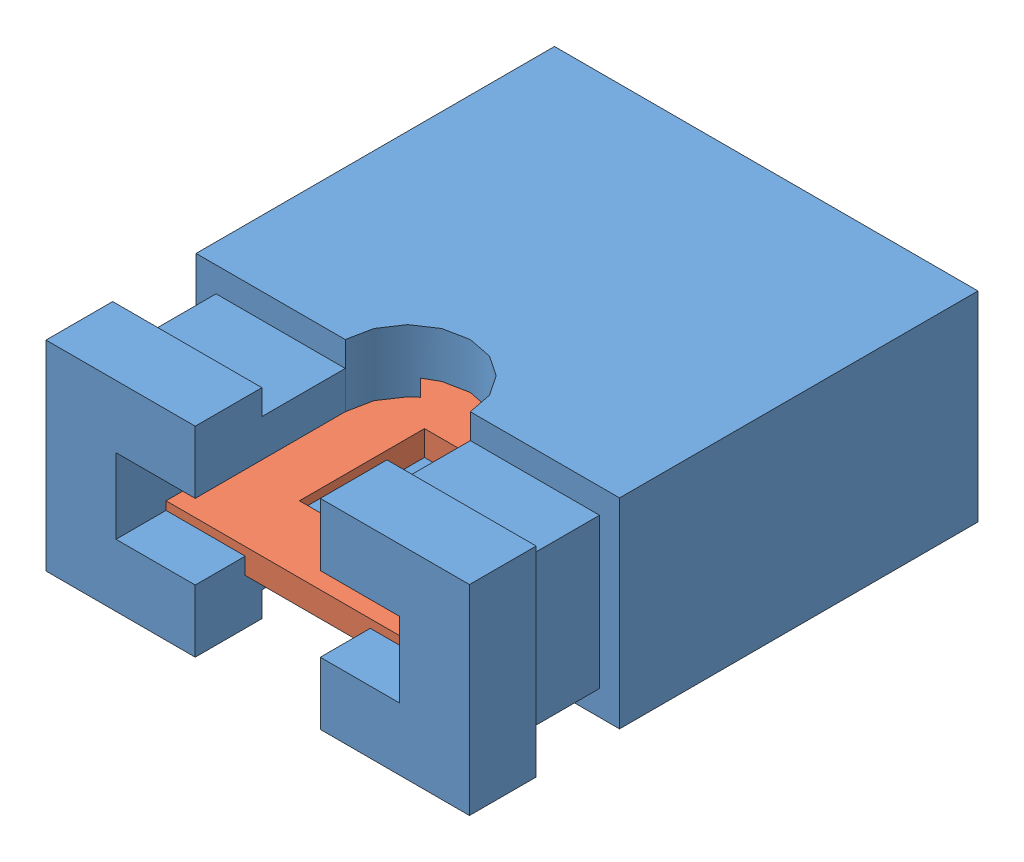
SolidWorks assembly MJ-0, configuration Default. Lengths in mm.
Overall size (5.08 2.4 6.1).
2 component instances, 2 part files, 0 mates.
Components (placement in the parent):
- MJ-0 plastic-1: MJ-0 plastic [Default] at origin size (5.08 2.4 6.1)
- MJ-0 metal-1: MJ-0 metal [Default] at (0 0 0.5) size (3.8 1.3 5)
